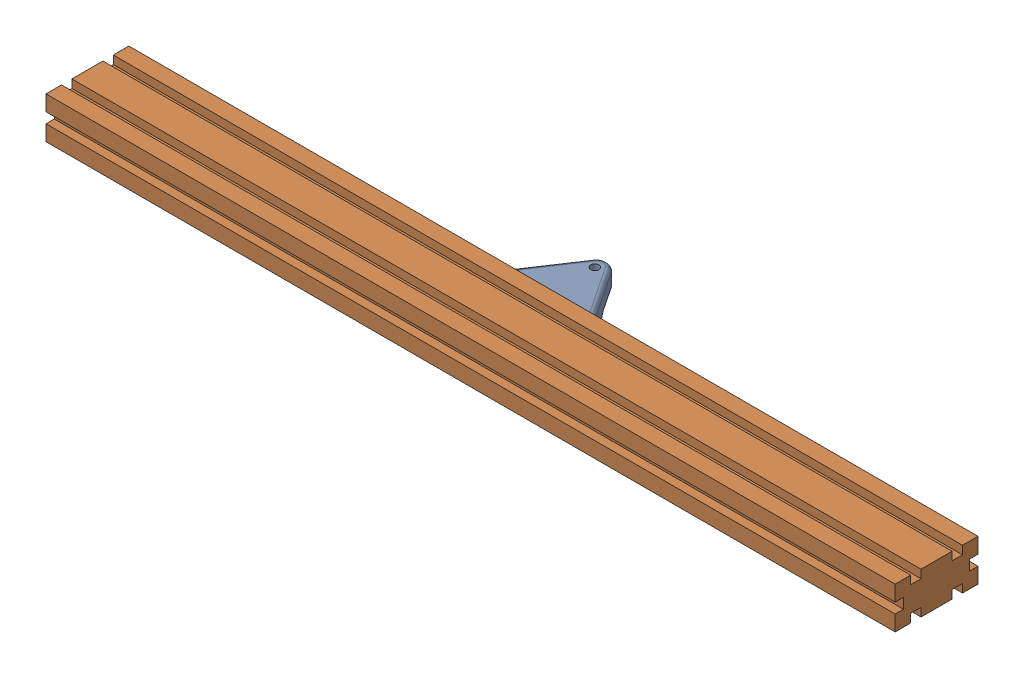
SolidWorks assembly Pivot av, configuration Défaut. Lengths in mm.
Overall size (410 20.11 65.75).
2 component instances, 2 part files, 14 mates.
Components (placement in the parent):
- pivot2024-2: pivot2024 [Défaut] at (185 0 -40) x (0 0 -1) z (-1 0 0) size (25.75 20.11 40)
- profilé 410 20 40 - Copie-2: profilé 410 20 40 - Copie [Défaut] at (0 -20 0) x (0 0 -1) z (1 0 0) size (40 20 410)
Mates (geometry in assembly coordinates):
- Coïncidente2: coincident aligned: plane of profilé 410 20 40 - Copie-1 through (-40 -20 0) normal (0 0 1)
- Coïncidente3: coincident aligned: plane of profilé 410 20 40 - Copie-1 through (0 -20 0) normal (1 0 0)
- Coïncidente4: coincident aligned: plane of profilé 410 20 40 - Copie-1 through (-40 0 0) normal (0 1 0)
- Coïncidente5: coincident anti-aligned: line of profilé 410 20 40 - Copie-1 through (-27.5 0 0) axis (1 0 0); line of pivot2024-1 through (-2.4037 0 0) axis (-1 0 0)
- Coïncidente6: coincident anti-aligned: line of profilé 410 20 40 - Copie-1 through (-40 -7.5 0) axis (0 1 0); line of pivot2024-1 through (-40 -2 0) axis (0 -1 0)
- Coaxiale1: concentric anti-aligned: cylinder of pivot2024-1 through (-20 -10 20) axis (0 -1 0) radius 2; cylinder of pivot2024-2 through (-20 -10 20) axis (0 1 0) radius 2
- Coïncidente7: coincident anti-aligned: plane of pivot2024-1 through (-40 -10 0) normal (0 1 0); plane of pivot2024-2 through (-35.6235 -10 43.5777) normal (0 -1 0)
- AngleLimite1: limit planar angle = 0.20019 rad anti-aligned: plane of pivot2024-2 through (-35.6235 -10 43.5777) normal (0.198856 0 0.980029); plane of pivot2024-1 through (-40 -10 0) normal (0 0 -1)
- Coïncidente9: coincident anti-aligned: plane of pivot2024-2 through (185 -10 71.4654) normal (0 0 1); plane of profilé 410 20 40 - Copie-2 through (410 -20 71.4654) normal (0 0 -1)
- Coïncidente10: coincident: point of pivot2024-2; unknown of profilé 410 20 40 - Copie-2
- Parallèle1: parallel aligned: line of pivot2024-2 through (225 -18 71.4654) axis (0 1 0); line of profilé 410 20 40 - Copie-2 through (410 -7.5 71.4654) axis (0 1 0)
- Coïncidente11: coincident aligned: plane of profilé 410 20 40 - Copie-2 through (410 0 0) normal (0 1 0)
- Coïncidente12: coincident anti-aligned: plane of profilé 410 20 40 - Copie-2 through (0 -20 0) normal (-1 0 0)
- Coïncidente13: coincident aligned: plane of profilé 410 20 40 - Copie-2 through (410 -20 0) normal (0 0 1)
